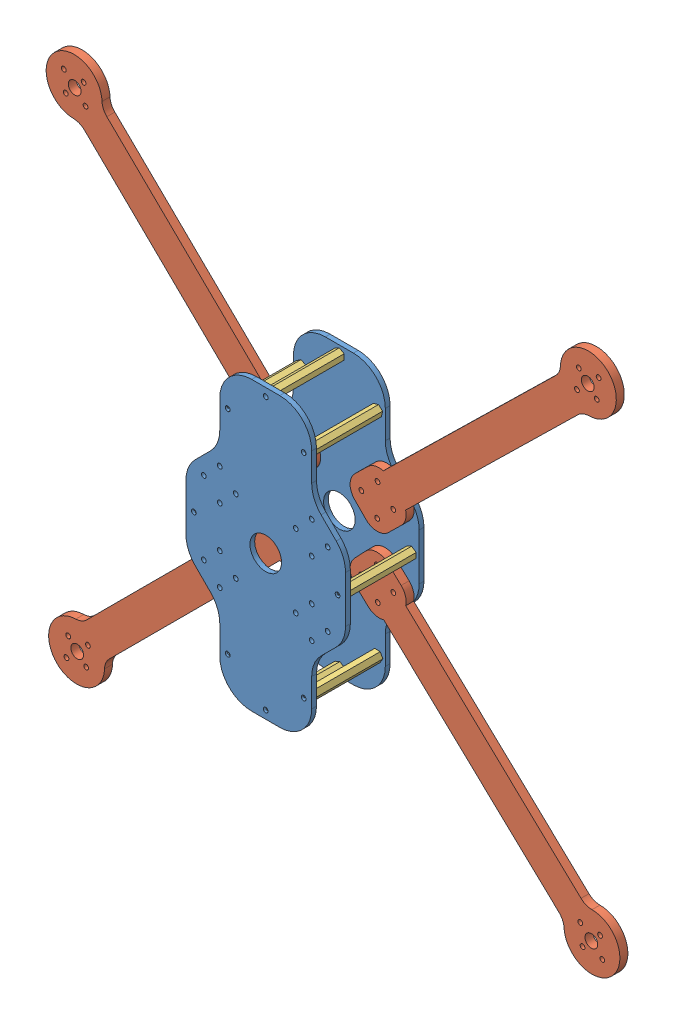
SolidWorks assembly Assem1, configuration Default. Lengths in mm.
Overall size (373.86 355.49 49.12).
15 component instances, 4 part files, 31 mates.
Components (placement in the parent):
- BasePlate-1: BasePlate [Default] at (315.0389 559.5108 888.1597) size (100 180 3)
- ArmPart-2: ArmPart [Default] at (225.435 641.702 896.1597) x (0.715504 -0.698609 0) z (0.698609 0.715504 0) size (217.5 5 35)
- ArmPart-3: ArmPart [Default] at (226.1481 476.4778 896.1597) x (0.707107 0.707107 0) z (-0.707107 0.707107 0) size (217.5 5 35)
- ArmPart-4: ArmPart [Default] at (404.562 641.7984 891.1597) x (-0.714551 -0.699583 0) z (-0.699583 0.714551 0) size (217.5 5 35)
- Part2^Assem1-1: Part2^Assem1 [Default] at origin (virtual)
- ArmPart-5: ArmPart [Default] at (405.5883 478.4681 896.1597) x (-0.726665 0.686992 0) z (-0.686992 -0.726665 0) size (217.5 5 35)
- spacer-1: spacer [Default] at (315.0389 644.5108 934.2814) x (1 0 0) z (0 1 0) size (6 45 6.93)
- spacer-25: spacer [Default] at (338.8257 626.0858 936.1597) x (-0.298183 0.954509 0) z (-0.954509 -0.298183 0) size (6 45 6.93)
- spacer-64: spacer [Default] at (360.0389 559.5108 936.1597) x (-0.433496 0.901156 0) z (-0.901156 -0.433496 0) size (6 45 6.93)
- spacer-77: spacer [Default] at (291.2521 626.0858 936.1597) x (-0.558465 0.829528 0) z (-0.829528 -0.558465 0) size (6 45 6.93)
- spacer-78: spacer [Default] at (270.0389 559.5108 936.1597) x (-0.671728 0.740798 0) z (-0.740798 -0.671728 0) size (6 45 6.93)
- spacer-79: spacer [Default] at (291.2521 492.9358 936.1597) x (-0.771785 0.635884 0) z (-0.635884 -0.771785 0) size (6 45 6.93)
- spacer-80: spacer [Default] at (338.8257 492.9358 936.1597) x (-0.85681 0.515632 0) z (-0.515632 -0.85681 0) size (6 45 6.93)
- spacer-85: spacer [Default] at (315.0389 474.5108 936.1597) x (0.399747 -0.916625 0) z (0.916625 0.399747 0) size (6 45 6.93)
- BasePlate-2: BasePlate [Default] at (315.0389 559.5108 934.2814) size (100 180 3)
Mates (geometry in assembly coordinates):
- Coincident2: coincident anti-aligned: plane of BasePlate-1 through (315.0389 559.5108 891.1597) normal (0 0 1); plane of ArmPart-2 through (225.435 641.702 891.1597) normal (0 0 -1)
- Concentric1: concentric anti-aligned: circle of BasePlate-1; circle of ArmPart-2
- Coincident6: coincident anti-aligned: plane of BasePlate-1 through (315.0389 559.5108 891.1597) normal (0 0 1); plane of ArmPart-3 through (226.1481 476.4778 891.1597) normal (0 0 -1)
- Parallel1: parallel aligned: plane of BasePlate-1 through (315.0389 559.5108 891.1597) normal (0 0 1); plane of ArmPart-3 through (226.1481 476.4778 896.1597) normal (0 0 1)
- Concentric5: concentric aligned: circle of BasePlate-1; circle of ArmPart-3
- Concentric6: concentric aligned: circle of BasePlate-1; circle of ArmPart-3
- Coincident17: coincident anti-aligned: plane of BasePlate-1 through (315.0389 559.5108 891.1597) normal (0 0 1); plane of ArmPart-4 through (404.562 641.7984 891.1597) normal (0 0 -1)
- Concentric12: concentric anti-aligned: circle of BasePlate-1; circle of ArmPart-4
- Coincident26: coincident anti-aligned: plane of BasePlate-1 through (315.0389 559.5108 891.1597) normal (0 0 1); plane of ArmPart-5 through (405.5883 478.4681 891.1597) normal (0 0 -1)
- Concentric13: concentric anti-aligned: circle of BasePlate-1; circle of ArmPart-5
- Parallel2: parallel anti-aligned: plane of BasePlate-1 through (315.0389 559.5108 891.1597) normal (0 0 1); plane of spacer-1 through (315.0389 644.5108 889.2814) normal (0 0 -1)
- Concentric14: concentric aligned: cylinder of BasePlate-1; cylinder of spacer-1 through (315.0389 644.5108 889.2814) axis (0 0 1) radius 1.5
- Parallel12: parallel anti-aligned: plane of BasePlate-1 through (315.0389 559.5108 891.1597) normal (0 0 1); plane of spacer-25 through (338.8257 626.0858 891.1597) normal (0 0 -1)
- Concentric29: concentric aligned: cylinder of BasePlate-1 through (338.8257 626.0858 888.1597) axis (0 0 1) radius 1.5; cylinder of spacer-25 through (338.8257 626.0858 891.1597) axis (0 0 1) radius 1.5
- Coincident38: coincident: plane of BasePlate-1 through (315.0389 559.5108 891.1597) normal (0 0 1); line of spacer-25 through (342.1322 627.1187 891.1597) axis (-0.219021 -0.97572 0)
- Coincident39: coincident: plane of BasePlate-1 through (315.0389 559.5108 891.1597) normal (0 0 1); line of spacer-64 through (363.1606 561.0125 891.1597) axis (-0.075159 -0.997172 0)
- Concentric30: concentric aligned: axis of BasePlate-1 through (360.0389 559.5108 888.1597) axis (0 0 1); cylinder of spacer-64 through (360.0389 559.5108 891.1597) axis (0 0 1) radius 1.5
- Coincident47: coincident: plane of BasePlate-1 through (315.0389 559.5108 891.1597) normal (0 0 1); line of spacer-77 through (294.1257 628.0204 891.1597) axis (0.068881 -0.997625 0)
- Concentric39: concentric aligned: circle of BasePlate-1; cylinder of spacer-77 through (291.2521 626.0858 891.1597) axis (0 0 1) radius 1.5
- Coincident48: coincident: plane of BasePlate-1 through (315.0389 559.5108 891.1597) normal (0 0 1); line of spacer-78 through (272.6051 561.8377 891.1597) axis (0.211335 -0.977414 0)
- Concentric40: concentric aligned: cylinder of BasePlate-1 through (270.0389 559.5108 888.1597) axis (0 0 1) radius 1.5; cylinder of spacer-78 through (270.0389 559.5108 891.1597) axis (0 0 1) radius 1.5
- Coincident49: coincident: plane of BasePlate-1 through (315.0389 559.5108 891.1597) normal (0 0 1); line of spacer-79 through (293.4549 495.6093 891.1597) axis (0.350443 -0.936584 0)
- Concentric41: concentric aligned: cylinder of BasePlate-1 through (291.2521 492.9358 888.1597) axis (0 0 1) radius 1.5; cylinder of spacer-79 through (291.2521 492.9358 891.1597) axis (0 0 1) radius 1.5
- Coincident50: coincident: plane of BasePlate-1 through (315.0389 559.5108 891.1597) normal (0 0 1); line of spacer-80 through (340.6119 495.9039 891.1597) axis (0.484204 -0.874955 0)
- Concentric42: concentric aligned: cylinder of BasePlate-1 through (338.8257 492.9358 888.1597) axis (0 0 1) radius 1.5; cylinder of spacer-80 through (338.8257 492.9358 891.1597) axis (0 0 1) radius 1.5
- Coincident54: coincident: plane of BasePlate-1 through (315.0389 559.5108 891.1597) normal (0 0 1); line of spacer-85 through (311.8636 473.126 891.1597) axis (0.112122 0.993694 0)
- Concentric47: concentric anti-aligned: circle of BasePlate-1; cylinder of spacer-85 through (315.0389 474.5108 891.1597) axis (0 0 1) radius 1.5
- Coincident55: coincident anti-aligned: plane of spacer-1 through (315.0389 644.5108 934.2814) normal (0 0 1); plane of BasePlate-2 through (315.0389 559.5108 934.2814) normal (0 0 -1)
- Concentric48: concentric aligned: cylinder of spacer-1 through (315.0389 644.5108 889.2814) axis (0 0 1) radius 1.5; cylinder of BasePlate-2 through (315.0389 644.5108 934.2814) axis (0 0 1) radius 1.5
- Concentric49: concentric anti-aligned: cylinder of spacer-85 through (315.0389 474.5108 891.1597) axis (0 0 1) radius 1.5; circle of BasePlate-2
- Concentric50: concentric aligned: cylinder of BasePlate-1 through (360.0389 559.5108 888.1597) axis (0 0 1) radius 1.5; cylinder of spacer-64 through (360.0389 559.5108 891.1597) axis (0 0 1) radius 1.5
